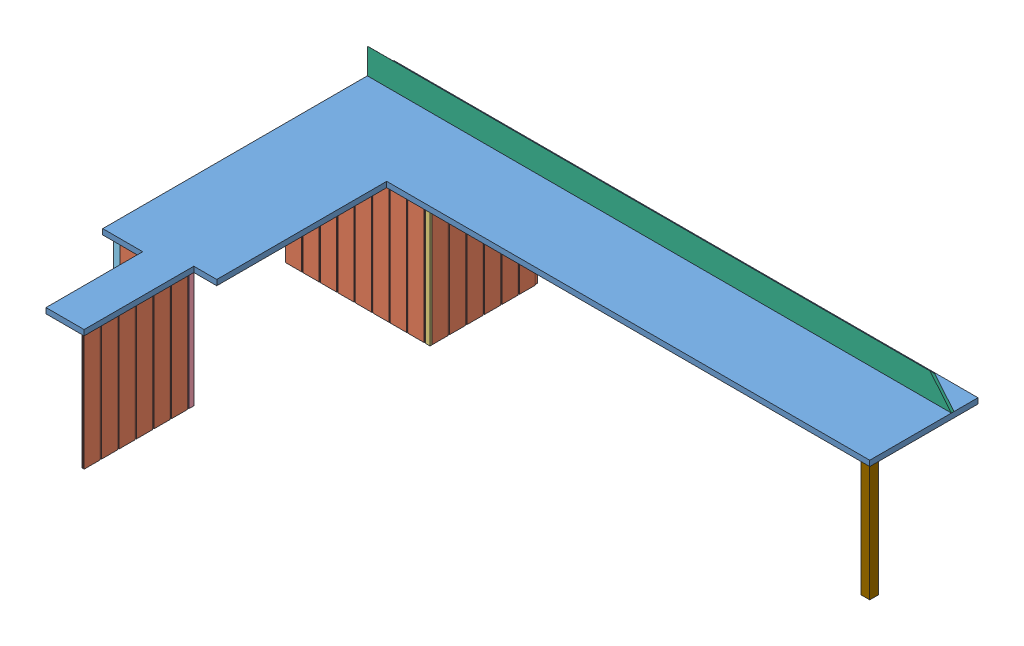
SolidWorks assembly Brüstung-Arbeit, configuration Standard. Lengths in mm.
Overall size (4046.49 1016.32 2687.4).
32 component instances, 9 part files, 94 mates.
Components (placement in the parent):
- Werkplatte-1: Werkplatte [Standard] at (-2563.2532 392.3163 2702.7833) size (4046.49 38 2687.4)
- Schalbrett-1: Schalbrett [Standard] at (-2381.7532 392.3163 3445.7833) x (1 0 0) z (0 0 -1) size (131 800 14)
- Schalbrett-2: Schalbrett [Standard] at (-2260.7532 392.3163 3445.7833) x (1 0 0) z (0 0 -1) size (131 800 14)
- Schalbrett-3: Schalbrett [Standard] at (-2139.7532 392.3163 3445.7833) x (1 0 0) z (0 0 -1) size (131 800 14)
- Schalbrett-4: Schalbrett [Standard] at (-2018.7532 392.3163 3445.7833) x (1 0 0) z (0 0 -1) size (131 800 14)
- Schalbrett-5: Schalbrett [Standard] at (-1897.7532 392.3163 3445.7833) x (1 0 0) z (0 0 -1) size (131 800 14)
- Schalbrett-6: Schalbrett [Standard] at (-1776.7532 392.3163 3445.7833) x (1 0 0) z (0 0 -1) size (131 800 14)
- Schalbrett-7: Schalbrett [Standard] at (-1655.7532 392.3163 3445.7833) x (1 0 0) z (0 0 -1) size (131 800 14)
- Schalbrett-15: Schalbrett [Standard] at (-2502.7532 392.3163 3445.7833) x (1 0 0) z (0 0 -1) size (131 800 14)
- Schalbrett-Ecke1-1: Schalbrett-Ecke1 [Standard] at (-1534.7532 392.3163 3445.7833) x (1 0 0) z (0 0 -1) size (32 800 14)
- Schalbrett-9: Schalbrett [Standard] at (-1570.2532 392.3163 3378.2833) x (0 0 -1) z (-1 0 0) size (131 800 14)
- Schalbrett-10: Schalbrett [Standard] at (-1570.2532 392.3163 3257.2833) x (0 0 -1) z (-1 0 0) size (131 800 14)
- Schalbrett-11: Schalbrett [Standard] at (-1570.2532 392.3163 3136.2833) x (0 0 -1) z (-1 0 0) size (131 800 14)
- Schalbrett-12: Schalbrett [Standard] at (-1570.2532 392.3163 3015.2833) x (0 0 -1) z (-1 0 0) size (131 800 14)
- Schalbrett-13: Schalbrett [Standard] at (-1570.2532 392.3163 2894.2833) x (0 0 -1) z (-1 0 0) size (131 800 14)
- Schalbrett-14: Schalbrett [Standard] at (-1570.2532 392.3163 2773.2833) x (0 0 -1) z (-1 0 0) size (131 800 14)
- Schalbrett-16: Schalbrett [Standard] at (-2029.2532 392.3163 5329.6883) x (0 0 -1) z (-1 0 0) size (131 800 14)
- Schalbrett-17: Schalbrett [Standard] at (-2029.2532 392.3163 5208.6883) x (0 0 -1) z (-1 0 0) size (131 800 14)
- Schalbrett-18: Schalbrett [Standard] at (-2029.2532 392.3163 5087.6883) x (0 0 -1) z (-1 0 0) size (131 800 14)
- Schalbrett-19: Schalbrett [Standard] at (-2029.2532 392.3163 4966.6883) x (0 0 -1) z (-1 0 0) size (131 800 14)
- Schalbrett-20: Schalbrett [Standard] at (-2029.2532 392.3163 4845.6883) x (0 0 -1) z (-1 0 0) size (131 800 14)
- Schalbrett-21: Schalbrett [Standard] at (-2029.2532 392.3163 4724.6883) x (0 0 -1) z (-1 0 0) size (131 800 14)
- Schalbrett-23: Schalbrett [Standard] at (-2096.7532 392.3163 4637.1883) x (-1 0 0) z (0 0 1) size (131 800 14)
- Schalbrett-24: Schalbrett [Standard] at (-2217.7532 392.3163 4637.1883) x (-1 0 0) z (0 0 1) size (131 800 14)
- Schalbrett-25: Schalbrett [Standard] at (-2338.7532 392.3163 4637.1883) x (-1 0 0) z (0 0 1) size (131 800 14)
- Schalbrett-26: Schalbrett [Standard] at (-2459.7532 392.3163 4637.1883) x (-1 0 0) z (0 0 1) size (131 800 14)
- Schalbrett-Ecke2-1: Schalbrett-Ecke2 [Standard] at (-2029.2532 392.3163 4603.6883) x (0 0 -1) z (-1 0 0) size (34 800 14)
- Schalbrett-Ecke3-1: Schalbrett-Ecke3 [Standard] at (-2580.7532 392.3163 4637.1883) x (-1 0 0) z (0 0 1) size (43 800 14)
- Steckdosenleiste-1: Steckdosenleiste [Standard] at (-540.0103 519.4748 2868.9113) size (4046.49 178.32 18)
- Tunnel-Unten-1: Tunnel-Unten [Standard] at (-2488.2532 242.3163 4041.4883) x (0 0 -1) z (1 0 0) size (1177.4 18 150)
- Tunnel-Vorn-1: Tunnel-Vorn [Standard] at (-2431.2532 326.3163 4041.4883) x (0 0 -1) z (1 0 0) size (1177.4 132 18)
- Bein-1: Bein [Standard] at (1453.2326 -407.6837 3422.7833) size (60 800 60)
Mates (geometry in assembly coordinates):
- Deckungsgleich1: coincident: plane of Werkplatte-1 through (-2563.2532 392.3163 2702.7833) normal (0 -1 0); plane of Schalbrett-15 through (-2453.2532 392.3163 3448.7833) normal (0 1 0)
- Deckungsgleich2: coincident anti-aligned: plane of Werkplatte-1 through (-2563.2532 392.3163 2702.7833) normal (0 -1 0); plane of Schalbrett-1 through (-2332.2532 392.3163 3448.7833) normal (0 1 0)
- Deckungsgleich3: coincident anti-aligned: plane of Werkplatte-1 through (-2563.2532 392.3163 2702.7833) normal (0 -1 0); plane of Schalbrett-2 through (-2211.2532 392.3163 3448.7833) normal (0 1 0)
- Deckungsgleich4: coincident: plane of Werkplatte-1 through (-2563.2532 392.3163 2702.7833) normal (0 -1 0); plane of Schalbrett-3 through (-2090.2532 392.3163 3448.7833) normal (0 1 0)
- Deckungsgleich5: coincident anti-aligned: plane of Werkplatte-1 through (-2563.2532 392.3163 2702.7833) normal (0 -1 0); plane of Schalbrett-4 through (-1969.2532 392.3163 3448.7833) normal (0 1 0)
- Deckungsgleich6: coincident anti-aligned: plane of Werkplatte-1 through (-2563.2532 392.3163 2702.7833) normal (0 -1 0); plane of Schalbrett-5 through (-1848.2532 392.3163 3448.7833) normal (0 1 0)
- Deckungsgleich7: coincident: plane of Werkplatte-1 through (-2563.2532 392.3163 2702.7833) normal (0 -1 0); plane of Schalbrett-6 through (-1727.2532 392.3163 3448.7833) normal (0 1 0)
- Deckungsgleich8: coincident: plane of Werkplatte-1 through (-2563.2532 392.3163 2702.7833) normal (0 -1 0); plane of Schalbrett-7 through (-1606.2532 392.3163 3448.7833) normal (0 1 0)
- Deckungsgleich10: coincident aligned: plane of Werkplatte-1 through (-2563.2532 430.3163 4630.1883) normal (-1 0 0); plane of Schalbrett-15 through (-2563.2532 -407.6837 3447.7833) normal (-1 0 0)
- Deckungsgleich11: coincident anti-aligned: plane of Schalbrett-1 through (-2432.2532 -407.6837 3447.7833) normal (0 0 -1); plane of Schalbrett-15 through (-2442.2532 -407.6837 3447.7833) normal (0 0 1)
- Deckungsgleich12: coincident: plane of Schalbrett-1 through (-2321.2532 -407.6837 3447.7833) normal (0 0 1); plane of Schalbrett-2 through (-2311.2532 -407.6837 3447.7833) normal (0 0 -1)
- Deckungsgleich13: coincident: plane of Schalbrett-2 through (-2200.2532 -407.6837 3447.7833) normal (0 0 1); plane of Schalbrett-3 through (-2190.2532 -407.6837 3447.7833) normal (0 0 -1)
- Deckungsgleich14: coincident: plane of Schalbrett-3 through (-2079.2532 -407.6837 3447.7833) normal (0 0 1); plane of Schalbrett-4 through (-2069.2532 -407.6837 3447.7833) normal (0 0 -1)
- Deckungsgleich15: coincident: plane of Schalbrett-4 through (-1958.2532 -407.6837 3447.7833) normal (0 0 1); plane of Schalbrett-5 through (-1948.2532 -407.6837 3447.7833) normal (0 0 -1)
- Deckungsgleich16: coincident: plane of Schalbrett-5 through (-1837.2532 -407.6837 3447.7833) normal (0 0 1); plane of Schalbrett-6 through (-1827.2532 -407.6837 3447.7833) normal (0 0 -1)
- Deckungsgleich17: coincident: plane of Schalbrett-6 through (-1716.2532 -407.6837 3447.7833) normal (0 0 1); plane of Schalbrett-7 through (-1706.2532 -407.6837 3447.7833) normal (0 0 -1)
- Deckungsgleich19: coincident: plane of Werkplatte-1 through (-1863.2532 430.3163 3452.7833) normal (0 0 1); plane of Schalbrett-15 through (-2453.2532 -407.6837 3452.7833) normal (0 0 1)
- Deckungsgleich20: coincident: plane of Schalbrett-1 through (-2432.2532 -407.6837 3443.7833) normal (-1 0 0); plane of Schalbrett-15 through (-2432.2532 -407.6837 3447.7833) normal (1 0 0)
- Deckungsgleich21: coincident anti-aligned: plane of Schalbrett-1 through (-2311.2532 -407.6837 3447.7833) normal (1 0 0); plane of Schalbrett-2 through (-2311.2532 -407.6837 3443.7833) normal (-1 0 0)
- Deckungsgleich22: coincident: plane of Schalbrett-2 through (-2190.2532 -407.6837 3447.7833) normal (1 0 0); plane of Schalbrett-3 through (-2190.2532 -407.6837 3443.7833) normal (-1 0 0)
- Deckungsgleich23: coincident: plane of Schalbrett-3 through (-2069.2532 -407.6837 3447.7833) normal (1 0 0); plane of Schalbrett-4 through (-2069.2532 -407.6837 3443.7833) normal (-1 0 0)
- Deckungsgleich24: coincident anti-aligned: plane of Schalbrett-4 through (-1948.2532 -407.6837 3447.7833) normal (1 0 0); plane of Schalbrett-5 through (-1948.2532 -407.6837 3443.7833) normal (-1 0 0)
- Deckungsgleich25: coincident anti-aligned: plane of Schalbrett-5 through (-1827.2532 -407.6837 3447.7833) normal (1 0 0); plane of Schalbrett-6 through (-1827.2532 -407.6837 3443.7833) normal (-1 0 0)
- Deckungsgleich26: coincident: plane of Schalbrett-6 through (-1706.2532 -407.6837 3447.7833) normal (1 0 0); plane of Schalbrett-7 through (-1706.2532 -407.6837 3443.7833) normal (-1 0 0)
- Deckungsgleich28: coincident anti-aligned: plane of Werkplatte-1 through (-2563.2532 392.3163 2702.7833) normal (0 -1 0); plane of Schalbrett-Ecke1-1 through (-1485.2532 392.3163 3448.7833) normal (0 1 0)
- Deckungsgleich29: coincident anti-aligned: plane of Schalbrett-7 through (-1595.2532 -407.6837 3447.7833) normal (0 0 1); plane of Schalbrett-Ecke1-1 through (-1585.2532 -407.6837 3447.7833) normal (0 0 -1)
- Deckungsgleich30: coincident anti-aligned: plane of Schalbrett-7 through (-1585.2532 -407.6837 3447.7833) normal (1 0 0); plane of Schalbrett-Ecke1-1 through (-1585.2532 -407.6837 3443.7833) normal (-1 0 0)
- Deckungsgleich31: coincident anti-aligned: plane of Werkplatte-1 through (-2563.2532 392.3163 2702.7833) normal (0 -1 0); plane of Schalbrett-9 through (-1567.2532 392.3163 3328.7833) normal (0 1 0)
- Deckungsgleich32: coincident anti-aligned: plane of Werkplatte-1 through (-2563.2532 392.3163 2702.7833) normal (0 -1 0); plane of Schalbrett-10 through (-1567.2532 392.3163 3207.7833) normal (0 1 0)
- Deckungsgleich33: coincident anti-aligned: plane of Werkplatte-1 through (-2563.2532 392.3163 2702.7833) normal (0 -1 0); plane of Schalbrett-11 through (-1567.2532 392.3163 3086.7833) normal (0 1 0)
- Deckungsgleich34: coincident anti-aligned: plane of Werkplatte-1 through (-2563.2532 392.3163 2702.7833) normal (0 -1 0); plane of Schalbrett-12 through (-1567.2532 392.3163 2965.7833) normal (0 1 0)
- Deckungsgleich35: coincident anti-aligned: plane of Werkplatte-1 through (-2563.2532 392.3163 2702.7833) normal (0 -1 0); plane of Schalbrett-13 through (-1567.2532 392.3163 2844.7833) normal (0 1 0)
- Deckungsgleich36: coincident anti-aligned: plane of Werkplatte-1 through (-2563.2532 392.3163 2702.7833) normal (0 -1 0); plane of Schalbrett-14 through (-1567.2532 392.3163 2723.7833) normal (0 1 0)
- Deckungsgleich37: coincident anti-aligned: plane of Schalbrett-Ecke1-1 through (-1474.2532 -407.6837 3438.7833) normal (0 0 -1); plane of Schalbrett-9 through (-1568.2532 -407.6837 3438.7833) normal (0 0 1)
- Deckungsgleich38: coincident aligned: plane of Schalbrett-Ecke1-1 through (-1563.2532 592.3163 3438.7833) normal (1 0 0); plane of Schalbrett-9 through (-1563.2532 -407.6837 3328.7833) normal (1 0 0)
- Deckungsgleich39: coincident anti-aligned: plane of Schalbrett-9 through (-1568.2532 -407.6837 3317.7833) normal (1 0 0); plane of Schalbrett-10 through (-1568.2532 -407.6837 3307.7833) normal (-1 0 0)
- Deckungsgleich40: coincident anti-aligned: plane of Schalbrett-10 through (-1568.2532 -407.6837 3196.7833) normal (1 0 0); plane of Schalbrett-11 through (-1568.2532 -407.6837 3186.7833) normal (-1 0 0)
- Deckungsgleich41: coincident anti-aligned: plane of Schalbrett-11 through (-1568.2532 -407.6837 3075.7833) normal (1 0 0); plane of Schalbrett-12 through (-1568.2532 -407.6837 3065.7833) normal (-1 0 0)
- Deckungsgleich42: coincident anti-aligned: plane of Schalbrett-12 through (-1568.2532 -407.6837 2954.7833) normal (1 0 0); plane of Schalbrett-13 through (-1568.2532 -407.6837 2944.7833) normal (-1 0 0)
- Deckungsgleich43: coincident anti-aligned: plane of Schalbrett-13 through (-1568.2532 -407.6837 2833.7833) normal (1 0 0); plane of Schalbrett-14 through (-1568.2532 -407.6837 2823.7833) normal (-1 0 0)
- Deckungsgleich44: coincident anti-aligned: plane of Schalbrett-9 through (-1568.2532 -407.6837 3307.7833) normal (0 0 -1); plane of Schalbrett-10 through (-1572.2532 -407.6837 3307.7833) normal (0 0 1)
- Deckungsgleich45: coincident anti-aligned: plane of Schalbrett-10 through (-1568.2532 -407.6837 3186.7833) normal (0 0 -1); plane of Schalbrett-11 through (-1572.2532 -407.6837 3186.7833) normal (0 0 1)
- Deckungsgleich46: coincident anti-aligned: plane of Schalbrett-11 through (-1568.2532 -407.6837 3065.7833) normal (0 0 -1); plane of Schalbrett-12 through (-1572.2532 -407.6837 3065.7833) normal (0 0 1)
- Deckungsgleich47: coincident anti-aligned: plane of Schalbrett-12 through (-1568.2532 -407.6837 2944.7833) normal (0 0 -1); plane of Schalbrett-13 through (-1572.2532 -407.6837 2944.7833) normal (0 0 1)
- Deckungsgleich48: coincident anti-aligned: plane of Schalbrett-13 through (-1568.2532 -407.6837 2823.7833) normal (0 0 -1); plane of Schalbrett-14 through (-1572.2532 -407.6837 2823.7833) normal (0 0 1)
- Deckungsgleich49: coincident anti-aligned: plane of Werkplatte-1 through (-2563.2532 392.3163 2702.7833) normal (0 -1 0); plane of Schalbrett-16 through (-2026.2532 392.3163 5280.1883) normal (0 1 0)
- Deckungsgleich50: coincident anti-aligned: plane of Werkplatte-1 through (-2563.2532 392.3163 2702.7833) normal (0 -1 0); plane of Schalbrett-17 through (-2026.2532 392.3163 5159.1883) normal (0 1 0)
- Deckungsgleich51: coincident anti-aligned: plane of Werkplatte-1 through (-2563.2532 392.3163 2702.7833) normal (0 -1 0); plane of Schalbrett-18 through (-2026.2532 392.3163 5038.1883) normal (0 1 0)
- Deckungsgleich52: coincident anti-aligned: plane of Werkplatte-1 through (-2563.2532 392.3163 2702.7833) normal (0 -1 0); plane of Schalbrett-19 through (-2026.2532 392.3163 4917.1883) normal (0 1 0)
- Deckungsgleich53: coincident anti-aligned: plane of Werkplatte-1 through (-2563.2532 392.3163 2702.7833) normal (0 -1 0); plane of Schalbrett-20 through (-2026.2532 392.3163 4796.1883) normal (0 1 0)
- Deckungsgleich54: coincident anti-aligned: plane of Werkplatte-1 through (-2563.2532 392.3163 2702.7833) normal (0 -1 0); plane of Schalbrett-21 through (-2026.2532 392.3163 4675.1883) normal (0 1 0)
- Deckungsgleich56: coincident anti-aligned: plane of Werkplatte-1 through (-2563.2532 392.3163 2702.7833) normal (0 -1 0); plane of Schalbrett-23 through (-2146.2532 392.3163 4634.1883) normal (0 1 0)
- Deckungsgleich57: coincident anti-aligned: plane of Werkplatte-1 through (-2563.2532 392.3163 2702.7833) normal (0 -1 0); plane of Schalbrett-24 through (-2267.2532 392.3163 4634.1883) normal (0 1 0)
- Deckungsgleich58: coincident anti-aligned: plane of Werkplatte-1 through (-2563.2532 392.3163 2702.7833) normal (0 -1 0); plane of Schalbrett-25 through (-2388.2532 392.3163 4634.1883) normal (0 1 0)
- Deckungsgleich59: coincident anti-aligned: plane of Werkplatte-1 through (-2563.2532 392.3163 2702.7833) normal (0 -1 0); plane of Schalbrett-26 through (-2509.2532 392.3163 4634.1883) normal (0 1 0)
- Deckungsgleich61: coincident aligned: plane of Werkplatte-1 through (-2022.2532 430.3163 5390.1883) normal (0 0 1); plane of Schalbrett-16 through (-2027.2532 -407.6837 5390.1883) normal (0 0 1)
- Deckungsgleich62: coincident aligned: plane of Werkplatte-1 through (-2022.2532 430.3163 5390.1883) normal (1 0 0); plane of Schalbrett-16 through (-2022.2532 -407.6837 5280.1883) normal (1 0 0)
- Deckungsgleich63: coincident anti-aligned: plane of Schalbrett-16 through (-2027.2532 -407.6837 5269.1883) normal (1 0 0); plane of Schalbrett-17 through (-2027.2532 -407.6837 5259.1883) normal (-1 0 0)
- Deckungsgleich64: coincident anti-aligned: plane of Schalbrett-17 through (-2027.2532 -407.6837 5148.1883) normal (1 0 0); plane of Schalbrett-18 through (-2027.2532 -407.6837 5138.1883) normal (-1 0 0)
- Deckungsgleich65: coincident anti-aligned: plane of Schalbrett-18 through (-2027.2532 -407.6837 5027.1883) normal (1 0 0); plane of Schalbrett-19 through (-2027.2532 -407.6837 5017.1883) normal (-1 0 0)
- Deckungsgleich66: coincident anti-aligned: plane of Schalbrett-19 through (-2027.2532 -407.6837 4906.1883) normal (1 0 0); plane of Schalbrett-20 through (-2027.2532 -407.6837 4896.1883) normal (-1 0 0)
- Deckungsgleich67: coincident anti-aligned: plane of Schalbrett-20 through (-2027.2532 -407.6837 4785.1883) normal (1 0 0); plane of Schalbrett-21 through (-2027.2532 -407.6837 4775.1883) normal (-1 0 0)
- Deckungsgleich69: coincident anti-aligned: plane of Schalbrett-16 through (-2027.2532 -407.6837 5259.1883) normal (0 0 -1); plane of Schalbrett-17 through (-2031.2532 -407.6837 5259.1883) normal (0 0 1)
- Deckungsgleich70: coincident anti-aligned: plane of Schalbrett-17 through (-2027.2532 -407.6837 5138.1883) normal (0 0 -1); plane of Schalbrett-18 through (-2031.2532 -407.6837 5138.1883) normal (0 0 1)
- Deckungsgleich71: coincident anti-aligned: plane of Schalbrett-18 through (-2027.2532 -407.6837 5017.1883) normal (0 0 -1); plane of Schalbrett-19 through (-2031.2532 -407.6837 5017.1883) normal (0 0 1)
- Deckungsgleich72: coincident anti-aligned: plane of Schalbrett-19 through (-2027.2532 -407.6837 4896.1883) normal (0 0 -1); plane of Schalbrett-20 through (-2031.2532 -407.6837 4896.1883) normal (0 0 1)
- Deckungsgleich73: coincident anti-aligned: plane of Schalbrett-20 through (-2027.2532 -407.6837 4775.1883) normal (0 0 -1); plane of Schalbrett-21 through (-2031.2532 -407.6837 4775.1883) normal (0 0 1)
- Deckungsgleich75: coincident anti-aligned: plane of Werkplatte-1 through (-2563.2532 392.3163 2702.7833) normal (0 -1 0); plane of Schalbrett-Ecke2-1 through (-2026.2532 392.3163 4554.1883) normal (0 1 0)
- Deckungsgleich76: coincident anti-aligned: plane of Schalbrett-21 through (-2027.2532 -407.6837 4664.1883) normal (1 0 0); plane of Schalbrett-Ecke2-1 through (-2027.2532 -407.6837 4654.1883) normal (-1 0 0)
- Deckungsgleich77: coincident anti-aligned: plane of Schalbrett-21 through (-2027.2532 -407.6837 4654.1883) normal (0 0 -1); plane of Schalbrett-Ecke2-1 through (-2031.2532 -407.6837 4654.1883) normal (0 0 1)
- Deckungsgleich78: coincident anti-aligned: plane of Werkplatte-1 through (-2563.2532 392.3163 2702.7833) normal (0 -1 0); plane of Schalbrett-23 through (-2146.2532 392.3163 4634.1883) normal (0 1 0)
- Deckungsgleich79: coincident anti-aligned: plane of Schalbrett-23 through (-2036.2532 -407.6837 4644.1883) normal (1 0 0); plane of Schalbrett-Ecke2-1 through (-2036.2532 -407.6837 4543.1883) normal (-1 0 0)
- Deckungsgleich80: coincident aligned: plane of Schalbrett-23 through (-2146.2532 -407.6837 4630.1883) normal (0 0 -1); plane of Schalbrett-Ecke2-1 through (-2022.2532 -607.6837 4630.1883) normal (0 0 -1)
- Deckungsgleich81: coincident anti-aligned: plane of Schalbrett-23 through (-2157.2532 -407.6837 4635.1883) normal (0 0 -1); plane of Schalbrett-24 through (-2167.2532 -407.6837 4635.1883) normal (0 0 1)
- Deckungsgleich82: coincident anti-aligned: plane of Schalbrett-23 through (-2167.2532 -407.6837 4635.1883) normal (-1 0 0); plane of Schalbrett-24 through (-2167.2532 -407.6837 4639.1883) normal (1 0 0)
- Deckungsgleich83: coincident anti-aligned: plane of Schalbrett-24 through (-2278.2532 -407.6837 4635.1883) normal (0 0 -1); plane of Schalbrett-25 through (-2288.2532 -407.6837 4635.1883) normal (0 0 1)
- Deckungsgleich85: coincident anti-aligned: plane of Schalbrett-24 through (-2288.2532 -407.6837 4635.1883) normal (-1 0 0); plane of Schalbrett-25 through (-2288.2532 -407.6837 4639.1883) normal (1 0 0)
- Deckungsgleich86: coincident anti-aligned: plane of Schalbrett-25 through (-2409.2532 -407.6837 4635.1883) normal (-1 0 0); plane of Schalbrett-26 through (-2409.2532 -407.6837 4639.1883) normal (1 0 0)
- Deckungsgleich87: coincident anti-aligned: plane of Schalbrett-25 through (-2399.2532 -407.6837 4635.1883) normal (0 0 -1); plane of Schalbrett-26 through (-2409.2532 -407.6837 4635.1883) normal (0 0 1)
- Deckungsgleich93: coincident anti-aligned: plane of Schalbrett-26 through (-2530.2532 -407.6837 4635.1883) normal (-1 0 0); plane of Schalbrett-Ecke3-1 through (-2530.2532 -407.6837 4639.1883) normal (1 0 0)
- Deckungsgleich94: coincident anti-aligned: plane of Werkplatte-1 through (-2563.2532 392.3163 2702.7833) normal (0 -1 0); plane of Schalbrett-Ecke3-1 through (-2630.2532 392.3163 4634.1883) normal (0 1 0)
- Deckungsgleich96: coincident anti-aligned: plane of Schalbrett-26 through (-2520.2532 -407.6837 4635.1883) normal (0 0 -1); plane of Schalbrett-Ecke3-1 through (-2530.2532 -407.6837 4635.1883) normal (0 0 1)
- Deckungsgleich97: coincident anti-aligned: plane of Werkplatte-1 through (-2563.2532 430.3163 2702.7833) normal (0 1 0); plane of Steckdosenleiste-1 through (-2563.2532 430.3163 2886.9113) normal (0 -1 0)
- Deckungsgleich98: coincident aligned: plane of Werkplatte-1 through (-2563.2532 430.3163 4630.1883) normal (-1 0 0); plane of Steckdosenleiste-1 through (-2563.2532 430.3163 2886.9113) normal (-1 0 0)
- Abstand1: distance = 184.128 mm anti-aligned: plane of Werkplatte-1 through (1483.2326 430.3163 2702.7833) normal (0 0 -1); plane of Steckdosenleiste-1 through (-540.0103 519.4748 2886.9113) normal (0 0 1)
- Deckungsgleich101: coincident aligned: plane of Werkplatte-1 through (-2563.2532 430.3163 4630.1883) normal (-1 0 0); plane of Tunnel-Unten-1 through (-2563.2532 260.3163 4630.1883) normal (-1 0 0)
- Deckungsgleich102: coincident anti-aligned: plane of Schalbrett-26 through (-2509.2532 -407.6837 4630.1883) normal (0 0 -1); plane of Tunnel-Unten-1 through (-2563.2532 260.3163 4630.1883) normal (0 0 1)
- Deckungsgleich103: coincident aligned: plane of Tunnel-Unten-1 through (-2413.2532 260.3163 4630.1883) normal (1 0 0); plane of Tunnel-Vorn-1 through (-2413.2532 326.3163 4041.4883) normal (1 0 0)
- Deckungsgleich104: coincident anti-aligned: plane of Tunnel-Unten-1 through (-2488.2532 260.3163 4041.4883) normal (0 1 0); plane of Tunnel-Vorn-1 through (-2413.2532 260.3163 4630.1883) normal (0 -1 0)
- Deckungsgleich105: coincident anti-aligned: plane of Werkplatte-1 through (-2563.2532 392.3163 2702.7833) normal (0 -1 0); plane of Tunnel-Vorn-1 through (-2413.2532 392.3163 4630.1883) normal (0 1 0)
- Deckungsgleich108: coincident aligned: plane of Tunnel-Unten-1 through (-2563.2532 260.3163 4630.1883) normal (0 0 1); plane of Tunnel-Vorn-1 through (-2413.2532 260.3163 4630.1883) normal (0 0 1)
- Deckungsgleich109: coincident anti-aligned: plane of Werkplatte-1 through (-2563.2532 392.3163 2702.7833) normal (0 -1 0); plane of Bein-1 through (1453.2326 392.3163 3422.7833) normal (0 1 0)
- Deckungsgleich110: coincident aligned: plane of Werkplatte-1 through (1483.2326 430.3163 3452.7833) normal (1 0 0); plane of Bein-1 through (1483.2326 392.3163 3452.7833) normal (1 0 0)
- Deckungsgleich111: coincident aligned: plane of Werkplatte-1 through (-1863.2532 430.3163 3452.7833) normal (0 0 1); plane of Bein-1 through (1423.2326 392.3163 3452.7833) normal (0 0 1)
